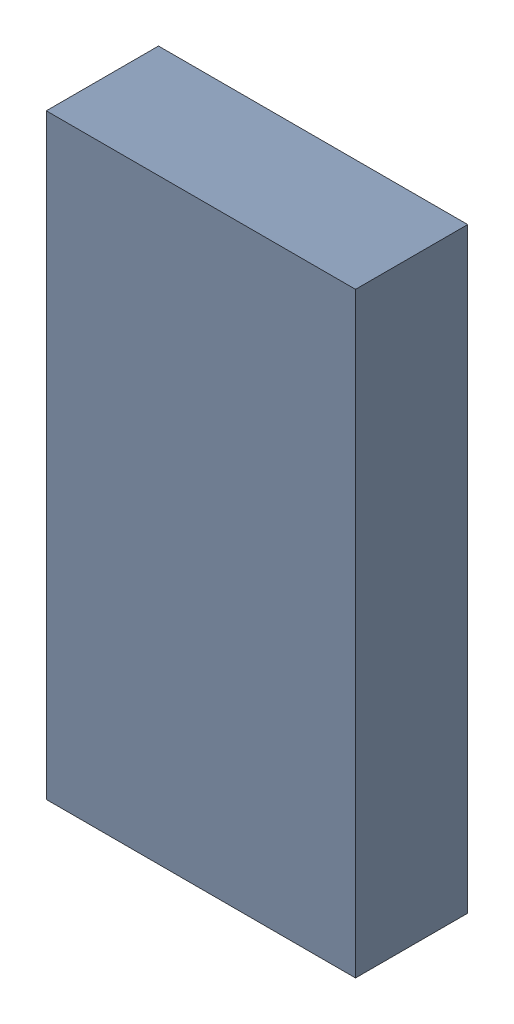
SolidWorks assembly 6327397120, configuration Default. Lengths in mm.
Overall size (0.7 1.35 0.25).
2 component instances, 1 part files, 0 mates.
Components (placement in the parent):
- 6701982208-1:  [Default] at (27.7 14.8 0) (suppressed, hidden)
- Extruded-1: Extruded [Default] at origin size (0.7 1.35 0.25)
